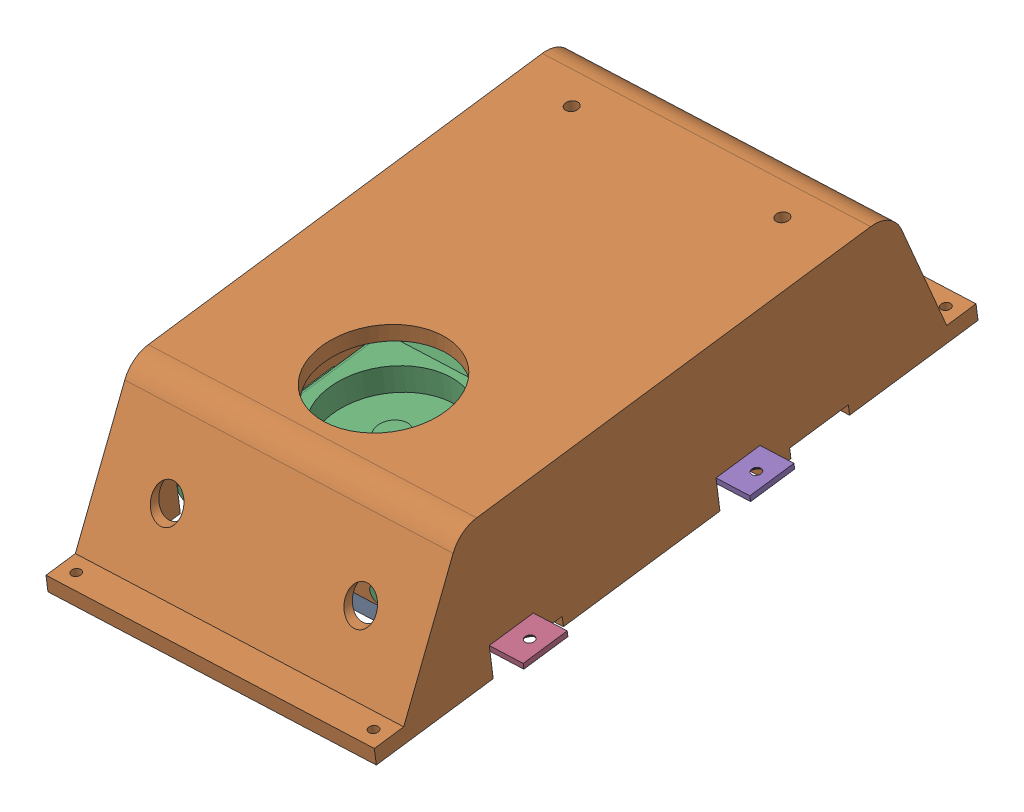
SolidWorks assembly BMS mount, configuration Default. Lengths in mm.
Overall size (256.55 145.29 422.85).
6 component instances, 5 part files, 13 mates.
Components (placement in the parent):
- BMS mount bottom-1: BMS mount bottom [Default] at (100.4264 -193.7547 -12.03) x (-0.999517 -0.021189 0.022753) z (-0.024964 0.110747 -0.993535) size (156 72 285)
- BMS mount top-1: BMS mount top [Default] at (98.9994 -117.2458 -3.4658) x (0.999517 0.021189 -0.022753) z (0.024964 -0.110747 0.993535) size (212 96 410)
- DALY BMS-1: DALY BMS [Default] at (101.9711 -165.3443 -0.3466) x (-0.999517 -0.021189 0.022753) z (-0.024964 0.110747 -0.993535) size (144 53.25 255)
- BMS mount bar-1: BMS mount bar [Default] at (104.723 -194.4135 93.4719) x (-0.024964 0.110747 -0.993535) z (-0.999517 -0.021189 0.022753) size (30 3.5 252)
- BMS mount bar-2: BMS mount bar [Default] at (100.866 -177.303 -60.0293) x (0.024964 -0.110747 0.993535) z (0.999517 0.021189 -0.022753) size (30 3.5 252)
- Balancer-1: Balancer [Default] at (96.2643 -142.4797 -147.1209) x (0.999517 0.021189 -0.022753) z (-0.018533 0.993623 0.111223) size (115 18.8 65)
Mates (geometry in assembly coordinates):
- Coincident2: coincident anti-aligned: plane of BMS mount top-1 through (30.3784 -198.2151 115.0463) normal (-0.024964 0.110747 -0.993535); plane of DALY BMS-1 through (54.9036 -179.3059 116.5378) normal (0.024964 -0.110747 0.993535)
- Parallel7: parallel aligned: plane of BMS mount top-1 through (100.2226 -182.8249 -10.8065) normal (0.018533 -0.993623 -0.111223); plane of DALY BMS-1 through (52.3381 -184.7858 -1.2666) normal (0.018533 -0.993623 -0.111223)
- Coincident13: coincident aligned: plane of BMS mount top-1 through (100.2226 -182.8249 -10.8065) normal (0.018533 -0.993623 -0.111223); plane of DALY BMS-1 through (52.3381 -184.7858 -1.2666) normal (0.018533 -0.993623 -0.111223)
- Coincident14: coincident anti-aligned: plane of DALY BMS-1 through (52.3381 -184.7858 -1.2666) normal (0.018533 -0.993623 -0.111223); plane of BMS mount bar-2 through (100.866 -177.303 -60.0293) normal (-0.018533 0.993623 0.111223)
- Concentric3: concentric anti-aligned: circle of DALY BMS-1; circle of BMS mount bar-2
- Concentric4: concentric aligned: circle of DALY BMS-1; circle of BMS mount bar-2
- Coincident17: coincident anti-aligned: plane of DALY BMS-1 through (52.3381 -184.7858 -1.2666) normal (0.018533 -0.993623 -0.111223); plane of BMS mount bar-1 through (104.723 -194.4135 93.4719) normal (-0.018533 0.993623 0.111223)
- Coincident18: coincident aligned: cylinder of DALY BMS-1 through (48.7626 -142.6637 100.6464) axis (0.018533 -0.993623 -0.111223) radius 1.5; circle of BMS mount bar-1
- Concentric5: concentric aligned: circle of DALY BMS-1; circle of BMS mount bar-1
- Concentric6: concentric anti-aligned: circle of BMS mount bottom-1; circle of BMS mount top-1
- Coincident22: coincident anti-aligned: plane of BMS mount bottom-1 through (100.2226 -182.8249 -10.8065) normal (-0.018533 0.993623 0.111223); plane of BMS mount top-1 through (100.2226 -182.8249 -10.8065) normal (0.018533 -0.993623 -0.111223)
- Coincident26: coincident aligned: circle of BMS mount bottom-1; circle of Balancer-1
- Coincident27: coincident anti-aligned: circle of BMS mount bottom-1; circle of Balancer-1
